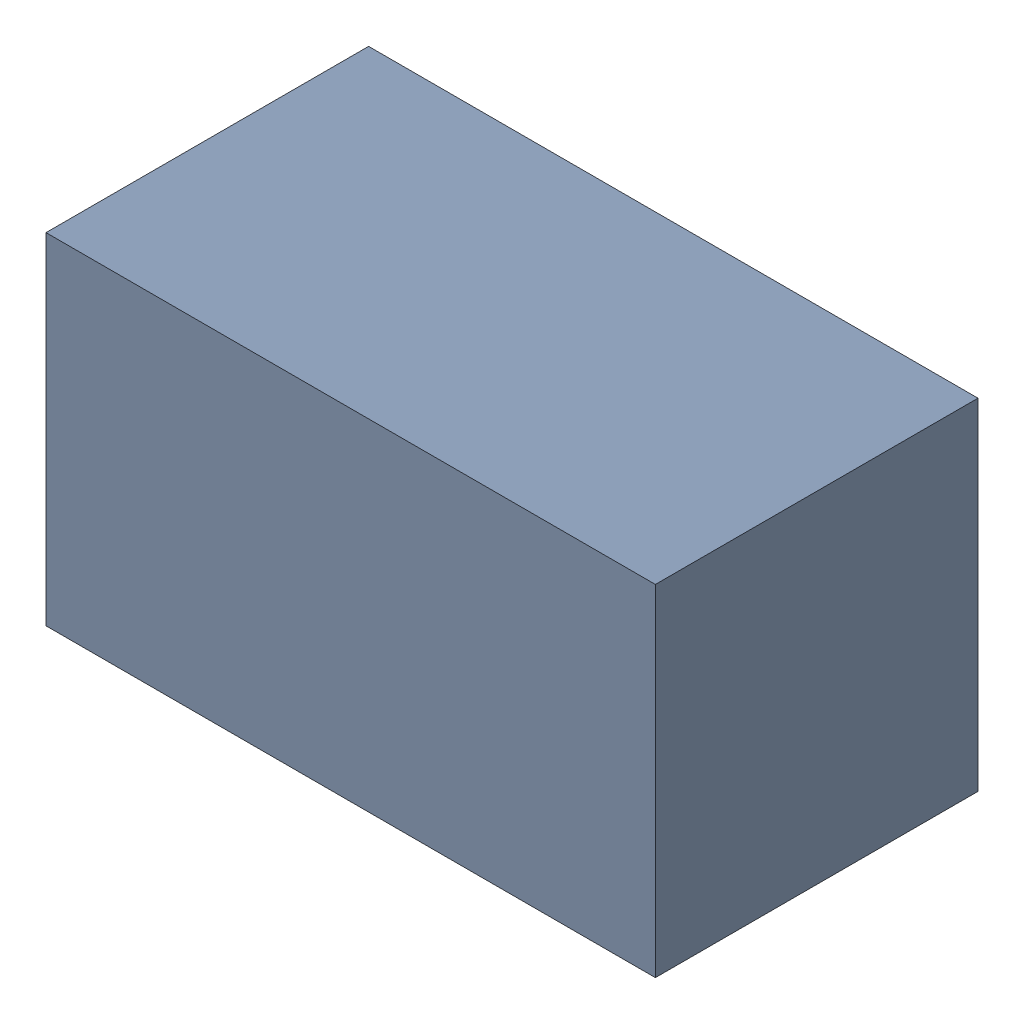
SolidWorks assembly R6, configuration Default. Lengths in mm.
Overall size (1.7 0.95 0.9).
2 component instances, 1 part files, 0 mates.
Components (placement in the parent):
- 580483600-1: 580483600 [Default] at (230.759 109.347 0) size (1.7 0.95 0.9)
  - Extruded_3-1: Extruded_3 [Default] at origin size (1.7 0.95 0.9)
